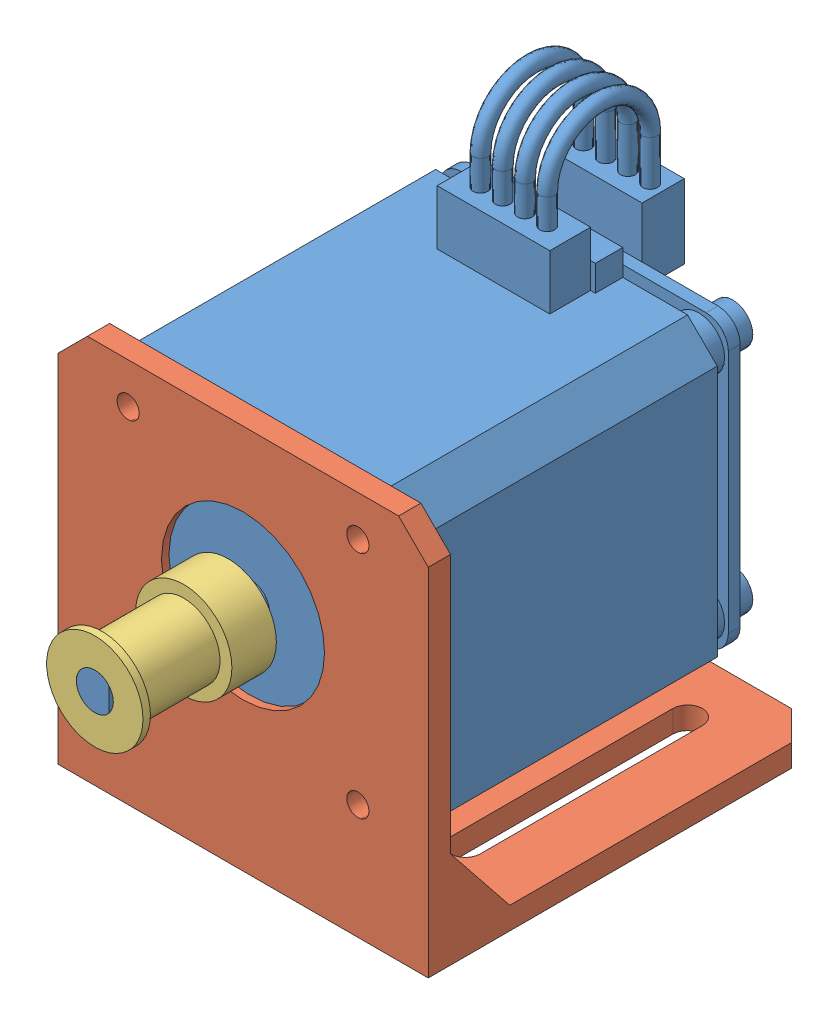
SolidWorks assembly stepper_subassy, configuration Default. Lengths in mm.
Overall size (50 71.4 73.3).
3 component instances, 3 part files, 6 mates.
Components (placement in the parent):
- smart stepper-1: smart stepper [Default] at origin size (45 61.4 73.3)
- stepper bracket-1: stepper bracket [Default] at (0 -5 3) x (-1 0 0) z (0 0 -1) size (50 52 53)
- pulley 16t-1: pulley 16t [Default] at (0 0 23) x (0 0 -1) z (1 0 0) size (18 13 13)
Mates (geometry in assembly coordinates):
- Concentric1: concentric anti-aligned: cylinder of smart stepper-1 through (0 0 2) axis (0 0 -1) radius 11; cylinder of stepper bracket-1 through (0 0 0) axis (0 0 1) radius 11
- Concentric2: concentric anti-aligned: cylinder of smart stepper-1 through (-15.5 15.5 23) axis (0 0 -1) radius 1.5; cylinder of stepper bracket-1 through (-15.5 15.5 0) axis (0 0 1) radius 1.5
- Coincident1: coincident anti-aligned: plane of smart stepper-1 through (0 0 0) normal (0 0 1); plane of stepper bracket-1 through (0 -5 0) normal (0 0 -1)
- Concentric3: concentric aligned: cylinder of smart stepper-1 through (0 0 -5.0502) axis (0 0 1) radius 2.5; cylinder of pulley 16t-1 through (0 0 5) axis (0 0 1) radius 2.5
- Coincident2: coincident aligned: plane of smart stepper-1 through (0 0 23) normal (0 0 1); plane of pulley 16t-1 through (0 0 23) normal (0 0 1)
- Coincident3: coincident aligned: plane of pulley 16t-1 through (0 0 23) normal (1 0 0)
